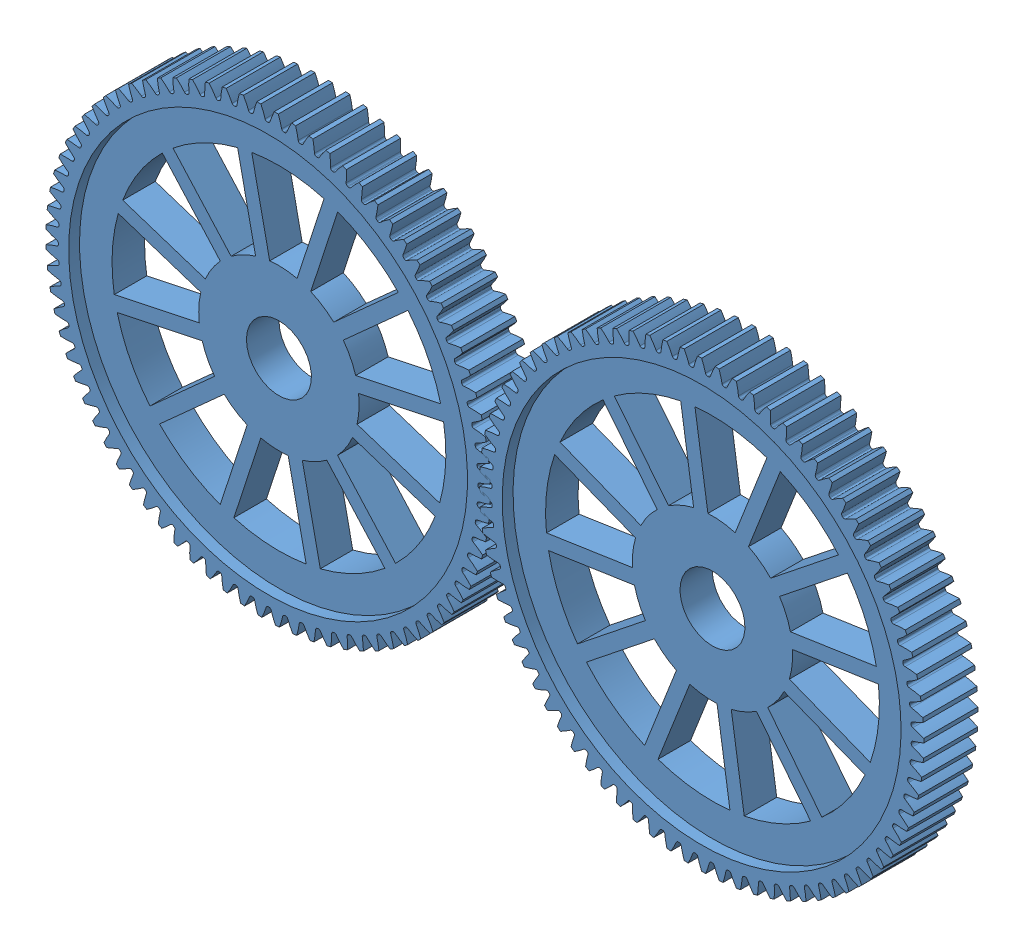
SolidWorks assembly Assem1, configuration Default. Lengths in mm.
Overall size (92.27 57.9 5).
2 component instances, 1 part files, 7 mates.
Components (placement in the parent):
- Main Gear 2-1: Main Gear 2 [Default] at (0 0 -24.4) x (0.743903 0.668288 0) z (0 0 1) size (41 41 5)
- Main Gear 2-2: Main Gear 2 [Default] at (40 0 -24.4) x (0.988844 0.148953 0) z (0 0 1) size (41 41 5)
Mates (geometry in assembly coordinates):
- Coincident4: coincident aligned: plane of Main Gear 2-1 through (0 0 0) normal (0 0 1); plane of Main Gear 2-2 through (40 0 0) normal (0 0 1)
- Coincident6: coincident: axis of Main Gear 2-1 through (0 0 -3) axis (0 0 1); plane of assembly
- Coincident7: coincident: axis of Main Gear 2-2 through (40 0 -3) axis (0 0 1); plane of assembly
- Distance3: distance = 40 mm: axis of Main Gear 2-1 through (0 0 -3) axis (0 0 1); axis of Main Gear 2-2 through (40 0 -3) axis (0 0 1)
- GearMate1: gear = 1 : 1 mm: axis of Main Gear 2-1 through (0 0 -3) axis (0 0 1); axis of Main Gear 2-2 through (40 0 -3) axis (0 0 1)
- Coincident9: coincident aligned: plane of Main Gear 2-1 through (0 0 0) normal (0 0 1); plane of assembly through (0 0 0) normal (0 0 1)
- Coincident10: coincident: axis of Main Gear 2-1 through (0 0 -3) axis (0 0 1); plane of assembly
